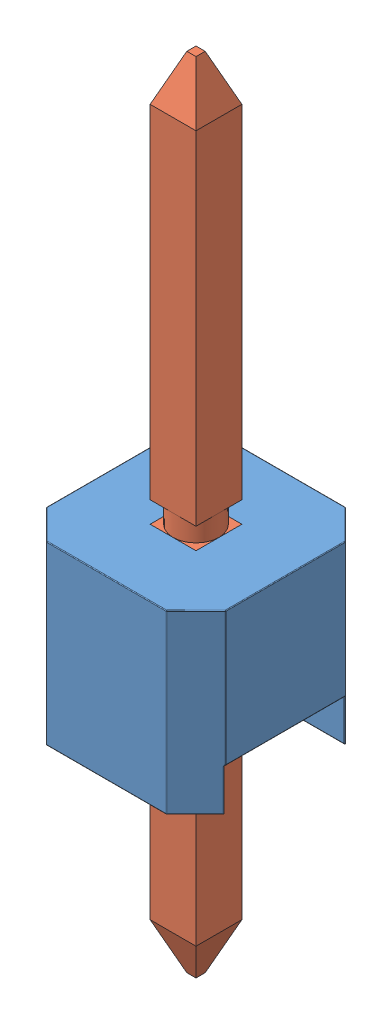
SolidWorks assembly C00033, configuration Pin Header Male 15mm 2.54mm-PITCH 1x01. Lengths in mm.
Overall size (2.54 15.3 2.54).
2 component instances, 2 part files, 4 mates.
Components (placement in the parent):
- C00033-PART-01-1: C00033-PART-01 [Default] at origin
- C00033-PART-02-1: C00033-PART-02 [15mm] at (1.27 -3 -1.27) size (0.65 15.3 0.65)
Mates (geometry in assembly coordinates):
- Coincident1: coordinate: point of Base-1
- Coincident3: coincident anti-aligned: plane of Base-1 through (1.595 0 -0.945) normal (0 0 -1); plane of C00033-PART-02-1 through (0.945 12.3 -0.945) normal (0 0 1)
- Coincident4: coincident anti-aligned: plane of Base-1 through (1.595 0 -0.945) normal (-1 0 0); plane of C00033-PART-02-1 through (1.595 12.3 -0.945) normal (1 0 0)
- Distance1: distance = 3 mm aligned: plane of Base-1 through (0 0 0) normal (0 -1 0); plane of C00033-PART-02-1 through (1.27 -3 -1.27) normal (0 -1 0)
